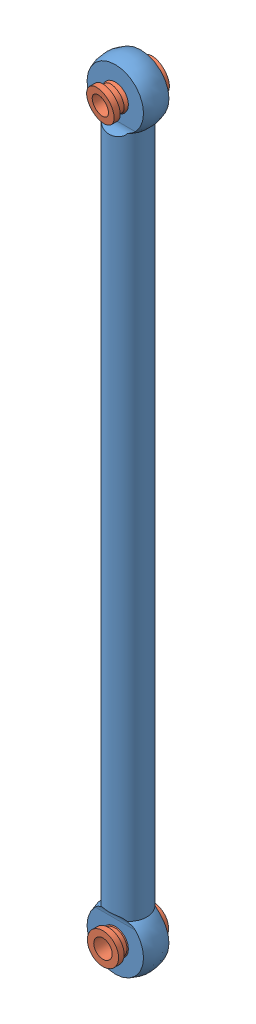
SolidWorks assembly Assem1, configuration Default. Lengths in mm.
Overall size (9.91 126.75 9.19).
3 component instances, 2 part files, 2 mates.
Components (placement in the parent):
- Control arm-1: Control arm [Default] at (-98.7255 11.1194 44.5417) size (9.91 126.75 6.1)
- control arm ball joint-1: control arm ball joint [Default] at (-98.7255 69.5394 44.5417) x (0.992241 -0.053506 0.112229) z (-0.117572 -0.110227 0.986928) size (5.7 5.7 8)
- control arm ball joint-2: control arm ball joint [Default] at (-98.7255 -47.3006 44.5417) size (5.7 5.7 8)
Mates (geometry in assembly coordinates):
- Concentric1: concentric: sphere of Control arm-1; sphere of control arm ball joint-1
- Concentric2: concentric: sphere of Control arm-1; sphere of control arm ball joint-2
